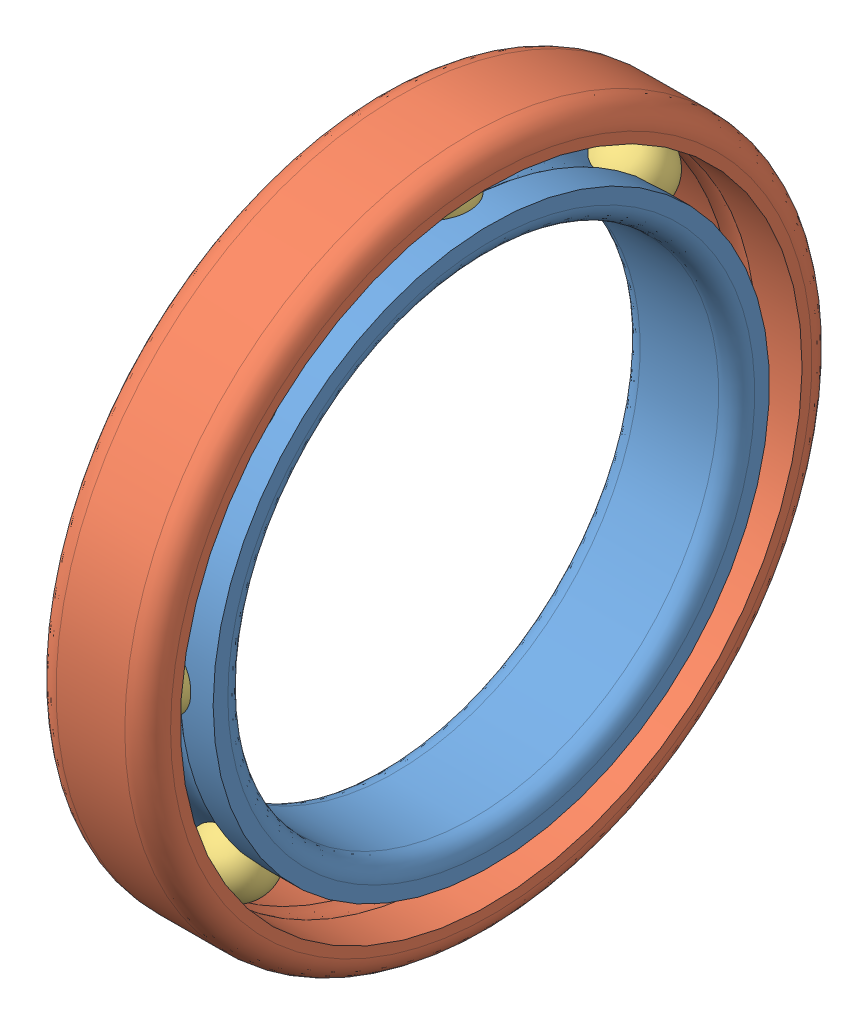
SolidWorks assembly Assemblage roulement, configuration Défaut. Lengths in mm.
Overall size (7 58.99 58.99).
10 component instances, 3 part files, 5 mates.
Components (placement in the parent):
- Bague roulement interieur-1: Bague roulement interieur [Défaut] at (-125.7423 41.326 -122.5987) size (7 34 34)
- Bague roulement exterieur-1: Bague roulement exterieur [Défaut] at (-125.7423 41.326 -122.5987) x (1 0 0) z (0 -0.620077 0.784541) size (7 42 42)
- bille roulement-10: bille roulement [Défaut] at (-125.7423 24.196 -122.5987) size (4.26 4.26 4.26)
- bille roulement-11: bille roulement [Défaut] at (-125.7423 29.2133 -110.486) x (1 0 0) z (0 0.707107 0.707107) size (4.26 4.26 4.26)
- bille roulement-12: bille roulement [Défaut] at (-125.7423 41.326 -105.4687) x (1 0 0) z (0 1 0) size (4.26 4.26 4.26)
- bille roulement-13: bille roulement [Défaut] at (-125.7423 53.4387 -110.486) x (1 0 0) z (0 0.707107 -0.707107) size (4.26 4.26 4.26)
- bille roulement-14: bille roulement [Défaut] at (-125.7423 58.456 -122.5987) x (1 0 0) z (0 0 -1) size (4.26 4.26 4.26)
- bille roulement-15: bille roulement [Défaut] at (-125.7423 53.4387 -134.7115) x (1 0 0) z (0 -0.707107 -0.707107) size (4.26 4.26 4.26)
- bille roulement-16: bille roulement [Défaut] at (-125.7423 41.326 -139.7287) x (1 0 0) z (0 -1 0) size (4.26 4.26 4.26)
- bille roulement-17: bille roulement [Défaut] at (-125.7423 29.2133 -134.7115) x (1 0 0) z (0 -0.707107 0.707107) size (4.26 4.26 4.26)
Mates (geometry in assembly coordinates):
- Coïncidente2: coincident aligned: plane of Bague roulement interieur-1 through (-125.7423 41.326 -122.5987) normal (0 0 1); plane of bille roulement-10 through (-125.7423 24.196 -122.5987) normal (0 0 1)
- Coïncidente3: coincident aligned: plane of Bague roulement interieur-1 through (-125.7423 41.326 -122.5987) normal (1 0 0); plane of bille roulement-10 through (-125.7423 24.196 -122.5987) normal (1 0 0)
- Tangent1: tangent anti-aligned: cylinder of Bague roulement interieur-1 through (-171.5641 41.326 -122.5987) axis (-1 0 0) radius 15; sphere of bille roulement-10
- Largeur1: width anti-aligned: plane of Bague roulement exterieur-1 through (-122.2423 57.8014 -109.5771) normal (1 0 0); plane of Bague roulement exterieur-1 through (-129.2423 57.8014 -109.5771) normal (-1 0 0); plane of Bague roulement interieur-1 through (-129.2423 57.426 -122.5987) normal (-1 0 0); plane of Bague roulement interieur-1 through (-122.2423 57.426 -122.5987) normal (1 0 0)
- Coaxiale1: concentric aligned: cylinder of Bague roulement interieur-1 through (-171.5641 41.326 -122.5987) axis (-1 0 0) radius 17; cylinder of Bague roulement exterieur-1 through (-165.9511 41.326 -122.5987) axis (-1 0 0) radius 19
